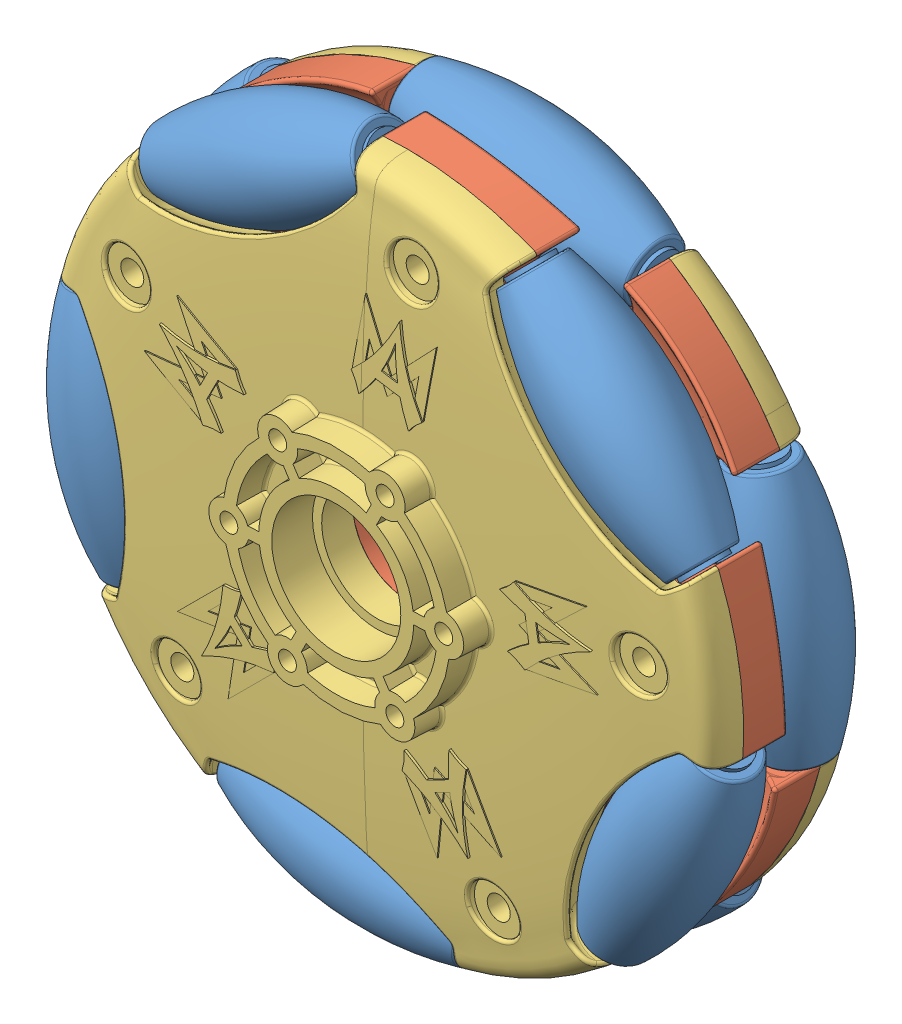
SolidWorks assembly am-3154+6inDuraOmni, configuration Default. Lengths in mm.
Overall size (212.33 212.48 93.3).
14 component instances, 3 part files, 0 mates.
Components (placement in the parent):
- Roller Assembly rev 2-1: Roller Assembly rev 2 [Default] at origin size (193.33 193.33 83.82)
  - MP6-10D Roller rev 2-1: MP6-10D Roller rev 2 [Default] at origin size (46.81 46.81 66.04)
  - MP6-10D Roller rev 2-2: MP6-10D Roller rev 2 [Default] x (0.309017 0.951057 0) z (0 0 1) size (46.81 46.81 66.04)
  - MP6-10D Roller rev 2-3: MP6-10D Roller rev 2 [Default] x (-0.809017 0.587785 0) z (0 0 1) size (46.81 46.81 66.04)
  - MP6-10D Roller rev 2-4: MP6-10D Roller rev 2 [Default] x (-0.809017 -0.587785 0) z (0 0 1) size (46.81 46.81 66.04)
  - MP6-10D Roller rev 2-5: MP6-10D Roller rev 2 [Default] x (0.309017 -0.951057 0) z (0 0 1) size (46.81 46.81 66.04)
  - MP6-10D Roller rev 2-6: MP6-10D Roller rev 2 [Default] at (0 0 -17.78) x (0.809017 0.587785 0) z (0 0 1) size (46.81 46.81 66.04)
  - MP6-10D Roller rev 2-7: MP6-10D Roller rev 2 [Default] at (0 0 -17.78) x (-0.309017 0.951057 0) z (0 0 1) size (46.81 46.81 66.04)
  - MP6-10D Roller rev 2-8: MP6-10D Roller rev 2 [Default] at (0 0 -17.78) x (-1 0 0) z (0 0 1) size (46.81 46.81 66.04)
  - MP6-10D Roller rev 2-9: MP6-10D Roller rev 2 [Default] at (0 0 -17.78) x (-0.309017 -0.951057 0) z (0 0 1) size (46.81 46.81 66.04)
  - MP6-10D Roller rev 2-10: MP6-10D Roller rev 2 [Default] at (0 0 -17.78) x (0.809017 -0.587785 0) z (0 0 1) size (46.81 46.81 66.04)
- MP6-10D Inner Body rev 2-1: MP6-10D Inner Body rev 2 [Default] at origin size (162.37 162.37 85.01)
- MP6-10D Outer Body-1: MP6-10D Outer Body [Default] at origin size (152.4 151.73 48.15)
- MP6-10D Outer Body-2: MP6-10D Outer Body [Default] at (0 0 -17.78) x (-0.587785 0.809017 0) z (0 0 -1) size (152.4 151.73 48.15)
